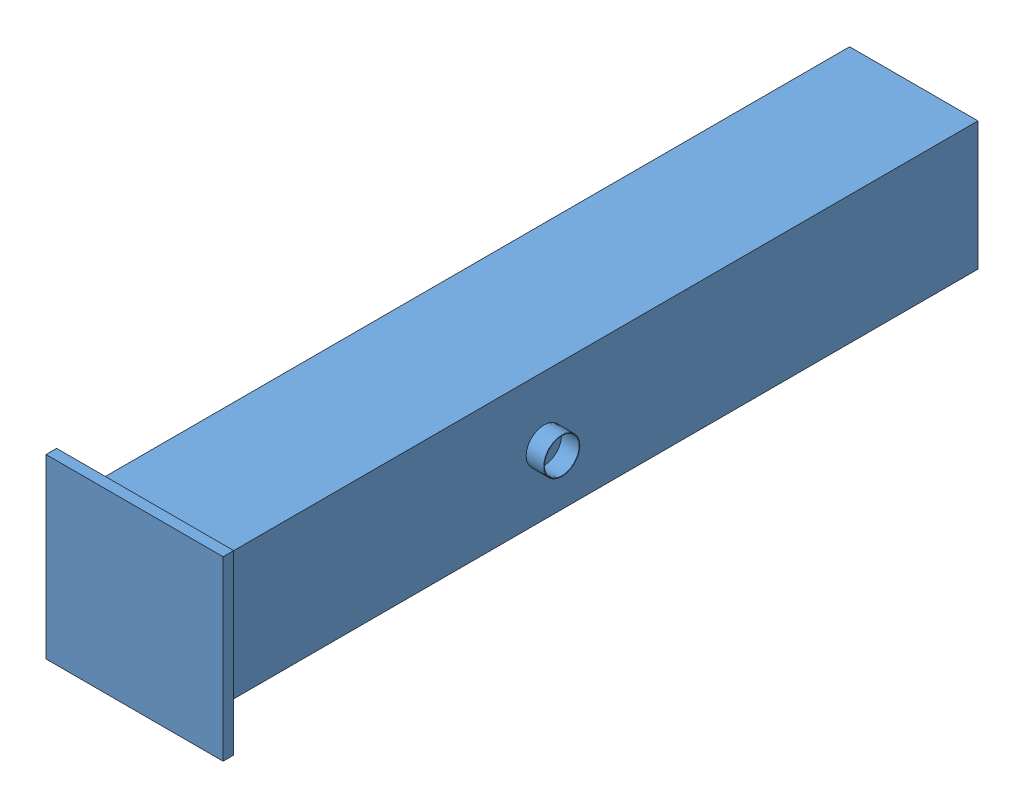
SolidWorks assembly Prigusivac, configuration Default. Lengths in mm.
Overall size (2000 2000 8800).
5 component instances, 3 part files, 8 mates.
Components (placement in the parent):
- Prigusivac-1: Prigusivac [Default] at (1209.4092 1602.1098 -1726.6385) size (2000 2000 8800)
- slip on weld flange-2: slip on weld flange [Slip On Flange 150-NPS24] at (334.4092 1602.1098 3173.3615) x (0 0 1) z (-1 0 0) size (812.8 812.8 82.56)
- slip on weld flange-3: slip on weld flange [Slip On Flange 150-NPS24] at (334.4092 1602.1098 -726.6385) x (0 0 1) z (-1 0 0) size (812.8 812.8 82.56)
- Poklopac-1: Poklopac [Default] at (334.4092 1602.1098 -726.6385) x (0 0 1) z (-1 0 0) size (812.8 812.8 30)
- Poklopac-3: Poklopac [Default] at (334.4092 1602.1098 3173.3615) x (0 0 1) z (-1 0 0) size (812.8 812.8 30)
Mates (geometry in assembly coordinates):
- Concentric21: concentric anti-aligned: cylinder of Prigusivac-1 through (334.4092 1602.1098 3173.3615) axis (1 0 0) radius 305; cylinder of slip on weld flange-2 through (416.9592 1602.1098 3173.3615) axis (-1 0 0) radius 331.724
- Coincident21: coincident aligned: plane of Prigusivac-1 through (334.4092 1602.1098 3173.3615) normal (-1 0 0); plane of slip on weld flange-2 through (334.4092 1602.1098 3173.3615) normal (-1 0 0)
- Concentric31: concentric anti-aligned: cylinder of Prigusivac-1 through (334.4092 1602.1098 -726.6385) axis (1 0 0) radius 305; cylinder of slip on weld flange-3 through (416.9592 1602.1098 -726.6385) axis (-1 0 0) radius 331.724
- Coincident31: coincident aligned: plane of Prigusivac-1 through (334.4092 1602.1098 -726.6385) normal (-1 0 0); plane of slip on weld flange-3 through (334.4092 1602.1098 -726.6385) normal (-1 0 0)
- InPlace1: in place: line of ? through (334.4092 1602.1098 -726.6385) axis (-1 0 0); plane of ? through (334.4092 0 0) normal (-1 0 0); moOrthogonalPlaneRef_w of ? through (334.4092 1602.1098 -726.6385) axis (-1 0 0); line of ? through (-55 334.4092 0) axis (0 0 1); line of ? through (334.4092 1602.1098 -726.6385) axis (-1 0 0); plane of ? through (334.4092 0 0) normal (0 0 1); plane of ? through (334.4092 1602.1098 -726.6385) normal (-1 0 0); unknown of ?
- Coincident4: coincident aligned: plane of slip on weld flange-3; plane of Poklopac-1
- Coincident5: coincident aligned: moOrthogonalPlaneRef_w of slip on weld flange-3 through (334.4092 1602.1098 -726.6385) axis (0 1 0); plane of Poklopac-1
- Coincident6: coincident anti-aligned: line of ? through (334.4092 1602.1098 -726.6385) axis (0 0 -1); plane of ? through (334.4092 1602.1098 -726.6385) normal (0 0 1)
